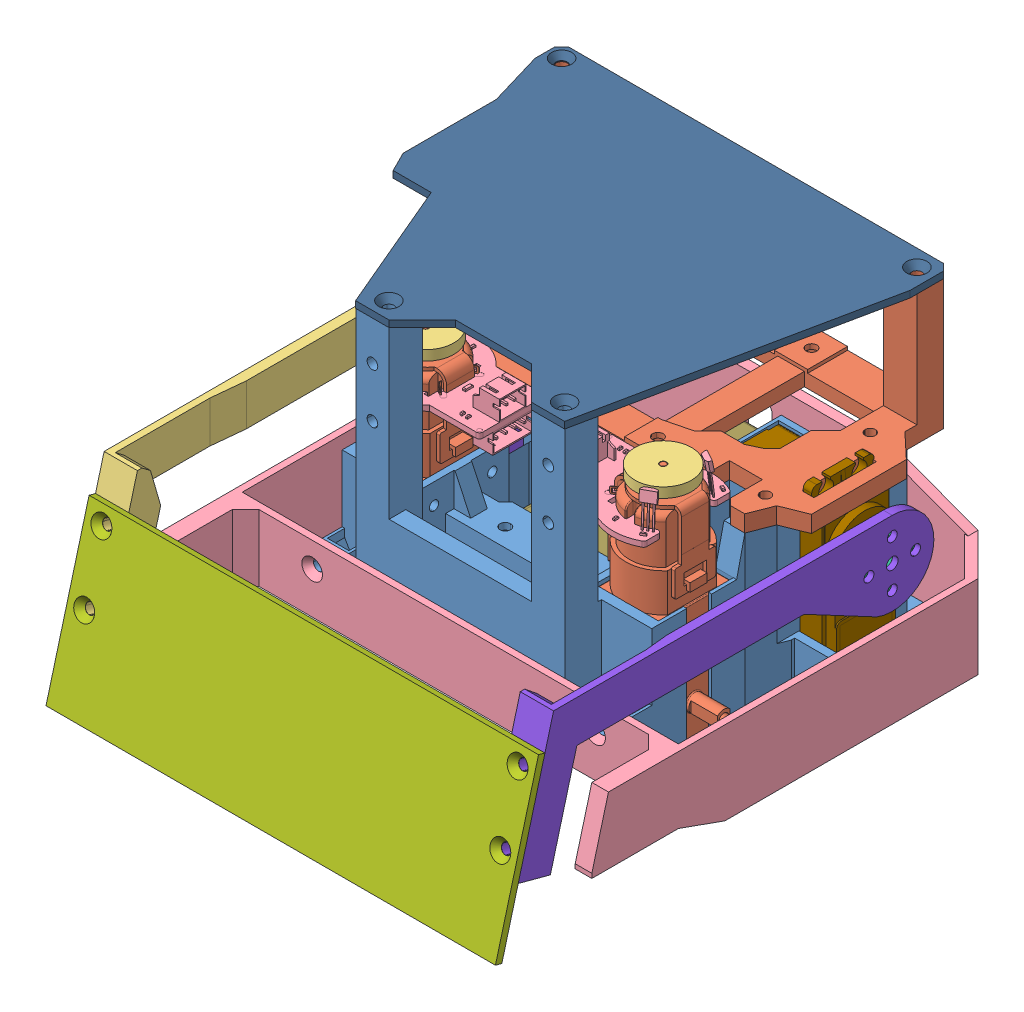
SolidWorks assembly Robot, configuration Default. Lengths in mm.
Overall size (135.9 102.07 156.64).
43 component instances, 26 part files, 28 mates.
Components (placement in the parent):
- MainBracing-1: MainBracing [Default] at origin size (131 90 97.6)
- ServoHolder-1: ServoHolder [Default] at (68.2155 21.731 -11.7065) size (124.15 39 59)
- RightArm-1: RightArm [Default] at (124.2792 -149.8432 39.6751) size (10 42.19 124.86)
- Bumper-1: Bumper [Default] at (64.7923 20.8808 88.6093) size (135 35 128.58)
- skf_bearing_608_2-1: skf_bearing_608_2 [Default] at (5.2909 61.8308 75.4593) x (1 0 0) z (0 0.991001 -0.133852) size (7 22 22)
  - skf_bearing_608_2_01-1: skf_bearing_608_2_01 [Default] at origin size (7 22 22)
  - skf_bearing_608_2_02-1: skf_bearing_608_2_02 [Default] at origin size (7 12.15 12.15)
  - skf_bearing_608_2_03-1: skf_bearing_608_2_03 [Default] at origin size (3.97 17.94 18.3)
- LeftArm-1: LeftArm [Default] at (92.9146 94.624 50.1938) x (1 0 0) z (0 -1 0) size (10 124.86 42.19)
- FeeTech FS5109M Metal Gear Servo Outer volume v1-1: FeeTech FS5109M Metal Gear Servo Outer volume v1 [Default] at (92.6923 56.6608 75.4593) x (0 0 -1) z (0 -1 0) size (20.1 41.4 54.6)
- PCBCover-1: PCBCover [Default] at (69.4522 -152.0652 -38.9418) x (1 0 -0.000001) z (0.000001 0 1) size (116.7 2 98)
- Pololu ball caster.-1: Pololu ball caster. [Default] at (101.9519 19.3568 53.3498) x (0.707107 0 -0.707107) z (0 -1 0) size (19.05 12.07 10.07)
- Pololu ball caster.-2: Pololu ball caster. [Default] at (38.8322 19.3568 53.5492) x (0.707107 0 0.707107) z (0 -1 0) size (19.05 12.07 10.07)
- 3.7V 2X 18650 BATTERY HOLDER WITH ON OFF SWITCH v1-1: 3.7V 2X 18650 BATTERY HOLDER WITH ON OFF SWITCH v1 [Default] at (70.2923 44.8808 87.6093) x (0 0 -1) z (-1 0 0) size (90.8 22 42.01)
  - 3.7V 2X 18650 BATTERY HOLDER WITH ON OFF SWITCH v1.step-1: 3.7V 2X 18650 BATTERY HOLDER WITH ON OFF SWITCH v1.step [Default] at origin size (90.8 22 42.01)
    - CASE, 3.7V 2X 18650 BATTERY HOLDER WITH ON OFF SWITCH.step-1: CASE, 3.7V 2X 18650 BATTERY HOLDER WITH ON OFF SWITCH.step [Default] at origin size (89 22 42.01)
    - SWITCH AND WIRING COVER, 3.7V 2X 18650 BATTERY HOLDER WITH ON OFF SWITCH.step-1: SWITCH AND WIRING COVER, 3.7V 2X 18650 BATTERY HOLDER WITH ON OFF SWITCH.step [Default] at (35.95 15 0) x (1 0 0) z (0 0 -1) size (11.3 3.7 38)
    - BATTERY CONDUCTION CLIP, 3.7V 2X 18650 BATTERY HOLDER WITH ON OFF SWITCH.step-1: BATTERY CONDUCTION CLIP, 3.7V 2X 18650 BATTERY HOLDER WITH ON OFF SWITCH.step [Default] at (-42.5 8.2 0) x (0 0 1) z (0 1 0) size (37 2.6 14)
    - SPRING, 3.7V 2X 18650 BATTERY HOLDER WITH ON OFF SWITCH.step-1: SPRING, 3.7V 2X 18650 BATTERY HOLDER WITH ON OFF SWITCH.step [Default] at (-37.0934 10.6 -9.5) x (0 0 -1) z (0 -1 0) size (7.33 10.2 7.44)
    - BATTERY CONDUCTION CLIP, POSITIVE TERMINAL, 3.7V 2X 18650 BATTERY HOLDER WITH ON OFF SWITCH.step-1: BATTERY CONDUCTION CLIP, POSITIVE TERMINAL, 3.7V 2X 18650 BATTERY HOLDER WITH ON OFF SWITCH.step [Default] at (30.1 7.7 -9.75) x (0 0 -1) z (0 1 0) size (15 6.6 13)
    - BATTERY CONDUCTION CLIP, NEGATIVE TERMINAL, 3.7V 2X 18650 BATTERY HOLDER WITH ON OFF SWITCH.step-1: BATTERY CONDUCTION CLIP, NEGATIVE TERMINAL, 3.7V 2X 18650 BATTERY HOLDER WITH ON OFF SWITCH.step [Default] at (30.1 7.7 9.75) x (0 0 -1) z (0 1 0) size (15 5.6 13)
    - SPRING, 3.7V 2X 18650 BATTERY HOLDER WITH ON OFF SWITCH.step-2: SPRING, 3.7V 2X 18650 BATTERY HOLDER WITH ON OFF SWITCH.step [Default] at (24.6934 9.6 9.75) x (0 0 -1) z (0 1 0) size (7.33 10.2 7.44)
    - SLIDE SWITCH SPDT, 3.7V 2X 18650 BATTERY HOLDER WITH ON OFF SWITCH_OFF.step-1: SLIDE SWITCH SPDT, 3.7V 2X 18650 BATTERY HOLDER WITH ON OFF SWITCH_OFF.step [Default] at (36.7 11.3 -8.7) x (0 0 -1) z (0 -1 0) size (19 12 6)
    - COVER, 3.7V 2X 18650 BATTERY HOLDER WITH ON OFF SWITCH.step-1: COVER, 3.7V 2X 18650 BATTERY HOLDER WITH ON OFF SWITCH.step [Default] at (1 22 0) x (1 0 0) z (0 0 -1) size (89.6 11.9 42)
- FIT0450 v11-1: FIT0450 v11 [Default] at (137.5898 -52.5151 23.9353) x (0 -1 0) z (1 0 0) size (73.48 29.86 44.39)
  - FIT0450 v11.step-1: FIT0450 v11.step [Default] at origin size (73.48 29.86 44.39)
    - MainMotor.step-1: MainMotor.step [Default] at (-75.3959 -81.4996 -19.2021) x (0 1 0) z (-1 0 0) size (22.6 29.93 73.35)
    - EncoderDisc.step-1: EncoderDisc.step [Default] at (-140.7459 -89.424 -31.5975) x (0 1 0) z (-1 0 0) size (17 17 3)
    - EncoderPCB.step-1: EncoderPCB.step [Default] at (-132.1949 -89.549 -31.5975) x (0 -1 0) z (-1 0 0) size (29.86 33.59 17.68)
    - EncoderHolder.step-1: EncoderHolder.step [Default] at (-44.9961 -114.5071 5.3229) x (0 1 0) z (-1 0 0) size (3.24 2.01 2.38)
    - EncoderHolder.step-2: EncoderHolder.step [Default] at (-44.9961 -64.3409 -68.5341) x (0 -1 0) z (-1 0 0) size (3.24 2.01 2.38)
- FIT0450 v11-2: FIT0450 v11 [Default] at (2.9948 -52.5151 202.7833) x (0 -1 0) z (-1 0 0) size (73.48 29.86 44.39)
  - FIT0450 v11.step-1: FIT0450 v11.step [Default] at origin size (73.48 29.86 44.39)
    - MainMotor.step-1: MainMotor.step [Default] at (-75.3959 -81.4996 -19.2021) x (0 1 0) z (-1 0 0) size (22.6 29.93 73.35)
    - EncoderDisc.step-1: EncoderDisc.step [Default] at (-140.7459 -89.424 -31.5975) x (0 1 0) z (-1 0 0) size (17 17 3)
    - EncoderPCB.step-1: EncoderPCB.step [Default] at (-132.1949 -89.549 -31.5975) x (0 -1 0) z (-1 0 0) size (29.86 33.59 17.68)
    - EncoderHolder.step-1: EncoderHolder.step [Default] at (-44.9961 -114.5071 5.3229) x (0 1 0) z (-1 0 0) size (3.24 2.01 2.38)
    - EncoderHolder.step-2: EncoderHolder.step [Default] at (-44.9961 -64.3409 -68.5341) x (0 -1 0) z (-1 0 0) size (3.24 2.01 2.38)
- Servo Hub v2-1: Servo Hub v2 [Default] at (149.2617 49.9753 73.6669) x (0 0.284851 0.958572) z (-1 0 0) size (20 20 4.5)
  - ServoHub v2.step-1: ServoHub v2.step [Default] at (5.0952 10.8538 14.0694) size (20 20 4.5)
    - ServoHub_1.step-1: ServoHub_1.step [Default] at origin size (20 20 4.5)
- FrontScoop-4: FrontScoop [Default] at (110.897 -158.3609 22.4592) size (135 48.81 14.87)
- BearingHolder-1: BearingHolder [Default] at (0 0.1 -0.15) size (14.6 52.95 25)
Mates (geometry in assembly coordinates):
- Concentric21: concentric anti-aligned: circle of LeftArm-1; circle of FeeTech FS5109M Metal Gear Servo Outer volume v1-1
- Concentric26: concentric aligned: cylinder of FeeTech FS5109M Metal Gear Servo Outer volume v1-1 through (134.0923 61.8308 75.4593) axis (-1 0 0) radius 2.85; cylinder of Servo Hub v2-1/ServoHub v2.step-1/ServoHub_1.step-1 through (133.1923 61.8308 75.4593) axis (-1 0 0) radius 2.85
- Coincident19: coincident anti-aligned: plane of FeeTech FS5109M Metal Gear Servo Outer volume v1-1 through (130.6923 61.8308 75.4593) normal (1 0 0); plane of Servo Hub v2-1/ServoHub v2.step-1/ServoHub_1.step-1 through (130.6923 61.8308 75.4593) normal (-1 0 0)
- Coincident20: coincident anti-aligned: plane of LeftArm-1 through (135.1923 61.8308 124.2093) normal (-1 0 0); plane of Servo Hub v2-1/ServoHub v2.step-1/ServoHub_1.step-1 through (135.1923 61.8308 75.4593) normal (1 0 0)
- Coincident24: coincident anti-aligned: plane of LeftArm-1 through (135.1923 53.3308 182.8324) normal (0 0.258819 0.965926); plane of FrontScoop-4 through (69.3923 40.5234 186.2641) normal (0 -0.258819 -0.965926)
- Coincident26: coincident anti-aligned: plane of ServoHolder-1 through (108.1922 71.8808 70.7755) normal (0 -1 0); plane of FeeTech FS5109M Metal Gear Servo Outer volume v1-1 through (125.8923 71.8808 84.0093) normal (0 1 0)
- Coincident30: coincident anti-aligned: plane of skf_bearing_608_2-1/skf_bearing_608_2_01-1 through (12.2909 60.4722 65.4006) normal (1 0 0); plane of BearingHolder-1 through (12.2909 61.8308 75.3893) normal (-1 0 0)
- Concentric31: concentric aligned: cylinder of skf_bearing_608_2-1/skf_bearing_608_2_01-1 through (8.7909 61.8308 75.4593) axis (-1 0 0) radius 11; circle of BearingHolder-1
- Concentric32: concentric aligned: cylinder of RightArm-1 through (11.8923 61.8308 75.4593) axis (-1 0 0) radius 4; cylinder of skf_bearing_608_2-1/skf_bearing_608_2_02-1 through (8.7909 61.8308 75.4593) axis (-1 0 0) radius 4
- Parallel4: parallel aligned: plane of RightArm-1 through (4.8923 74.3308 185.4593) normal (0 1 0); plane of Bumper-1 through (70.2923 45.8808 76.6093) normal (0 1 0)
- Concentric33: concentric aligned: cone of RightArm-1; cone of FrontScoop-4 through (6.8923 59.8419 181.0877) axis (0 -0.258819 -0.965926)
- Concentric34: concentric aligned: cylinder of LeftArm-1 through (131.8923 40.5234 186.2641) axis (0 -0.258819 -0.965926) radius 1.5; cone of FrontScoop-4 through (131.8923 40.5234 186.2641) axis (0 -0.258819 -0.965926)
- Coincident32: coincident anti-aligned: plane of ServoHolder-1 through (61.2422 110.8808 46.7755) normal (0 1 0); plane of PCBCover-1 through (61.2422 110.8808 89.7755) normal (0 -1 0)
- Coincident36: coincident anti-aligned: plane of MainBracing-1 through (128.6423 21.8808 41.0093) normal (0 0 -1); plane of Bumper-1 through (14.7923 20.8808 41.0093) normal (0 0 1)
- Coincident37: coincident anti-aligned: plane of MainBracing-1 through (92.6923 30.8808 85.7093) normal (1 0 0); plane of FeeTech FS5109M Metal Gear Servo Outer volume v1-1 through (92.6923 70.3808 84.0093) normal (-1 0 0)
- Coincident38: coincident anti-aligned: plane of MainBracing-1 through (94.6923 30.8808 65.4093) normal (0 0 1); plane of FeeTech FS5109M Metal Gear Servo Outer volume v1-1 through (125.8923 32.5808 65.4093) normal (0 0 -1)
- Coincident39: coincident anti-aligned: plane of RightArm-1 through (4.8923 53.3308 182.8324) normal (0 0.258819 0.965926); plane of FrontScoop-4 through (69.3923 40.5234 186.2641) normal (0 -0.258819 -0.965926)
- Concentric40: concentric aligned: cylinder of RightArm-1 through (6.8923 40.5234 186.2641) axis (0 -0.258819 -0.965926) radius 1.5; circle of FrontScoop-4
- Coincident42: coincident anti-aligned: plane of MainBracing-1 through (70.2923 22.8808 113.3593) normal (0 1 0); plane of FIT0450 v11-2/FIT0450 v11.step-1/MainMotor.step-1 through (25.2923 22.8808 102.1093) normal (0 -1 0)
- Coincident43: coincident anti-aligned: plane of MainBracing-1 through (25.2923 22.8808 102.1093) normal (0 0 1); plane of FIT0450 v11-2/FIT0450 v11.step-1/MainMotor.step-1 through (43.8923 59.8808 102.1093) normal (0 0 -1)
- Coincident44: coincident anti-aligned: plane of MainBracing-1 through (43.8923 22.8808 99.6093) normal (-1 0 0); plane of FIT0450 v11-2/FIT0450 v11.step-1/MainMotor.step-1 through (43.8923 55.5558 113.3593) normal (1 0 0)
- Coincident45: coincident anti-aligned: plane of MainBracing-1 through (70.2923 22.8808 113.3593) normal (0 1 0); plane of FIT0450 v11-1/FIT0450 v11.step-1/MainMotor.step-1 through (115.2923 22.8808 124.6093) normal (0 -1 0)
- Coincident46: coincident anti-aligned: plane of MainBracing-1 through (115.2923 22.8808 124.6093) normal (0 0 -1); plane of FIT0450 v11-1/FIT0450 v11.step-1/MainMotor.step-1 through (96.6923 59.8808 124.6093) normal (0 0 1)
- Coincident47: coincident anti-aligned: plane of MainBracing-1 through (96.6923 22.8808 127.1093) normal (1 0 0); plane of FIT0450 v11-1/FIT0450 v11.step-1/MainMotor.step-1 through (96.6923 55.5558 113.3593) normal (-1 0 0)
- Concentric41: concentric anti-aligned: circle of ServoHolder-1; circle of PCBCover-1
- Concentric42: concentric aligned: cylinder of ServoHolder-1 through (6.8922 98.8808 44.7756) axis (0 1 0) radius 1.6; circle of PCBCover-1
- Concentric43: concentric aligned: circle of MainBracing-1; circle of Bumper-1
- Concentric44: concentric anti-aligned: circle of MainBracing-1; circle of Bumper-1
